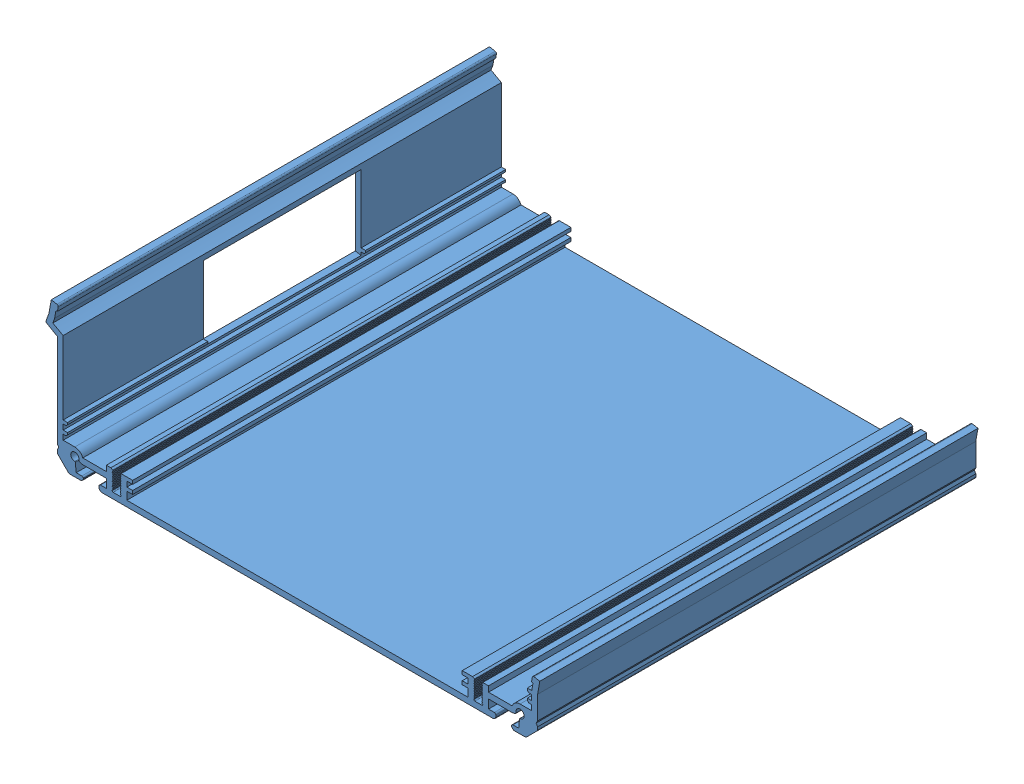
SolidWorks assembly 92850150_ATPH1850-0150, configuration Predeterminado. Lengths in mm.
Overall size (169.02 48.5 150).
3 component instances, 2 part files, 0 mates.
Components (placement in the parent):
- 92850150_ATPH1850-0150.stp-1: 92850150_ATPH1850-0150.stp [Predeterminado] at origin size (181.17 53.24 150)
  - 1009505_3DSYM015.stp-1: 1009505_3DSYM015.stp [Predeterminado] at origin size (169.02 48.5 150)
  - 1009506_3DSYM.stp-1: 1009506_3DSYM.stp [Predeterminado] at (0.5182 8.1983 150) size (181.17 41.58 150) (hidden)
